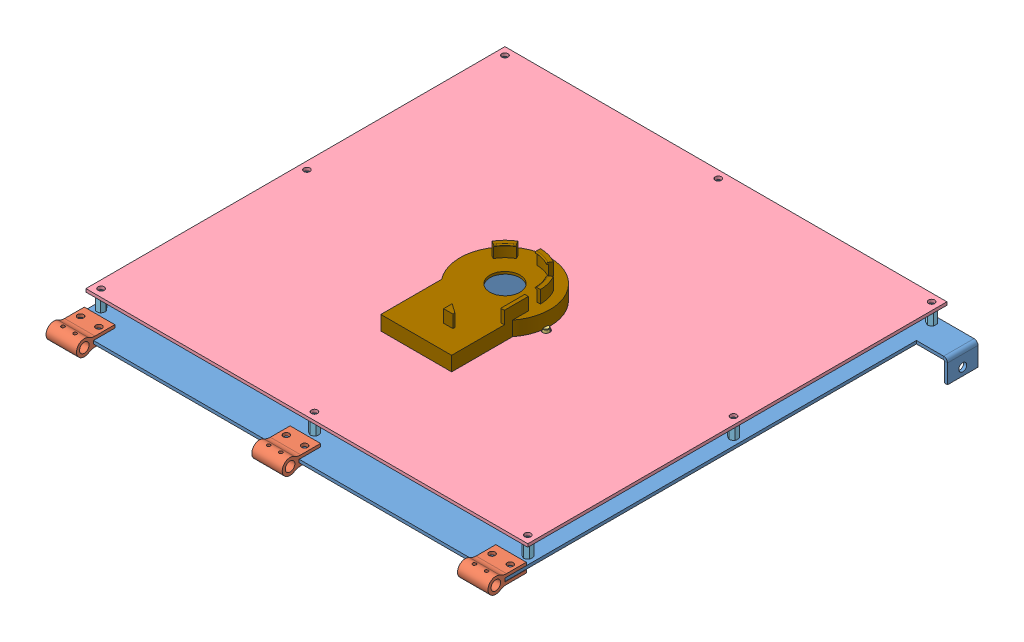
SolidWorks assembly WrenchPlateAssem, configuration Default. Lengths in mm.
Overall size (394.21 74.37 382.46).
21 component instances, 10 part files, 40 mates.
Components (placement in the parent):
- WrenchPlate-1: WrenchPlate [Default] at (-60.1457 196.6895 471.773) size (394.21 19.05 368.3)
- ShaftPanelHolder-1: ShaftPanelHolder [Default] at (282.7543 195.2925 479.393) x (0 -1 0) z (0 0 1) size (13.08 25.4 31.94)
- ShaftPanelHolder-2: ShaftPanelHolder [Default] at (111.3043 195.2925 479.393) x (0 -1 0) z (0 0 1) size (13.08 25.4 31.94)
- ShaftPanelHolder-3: ShaftPanelHolder [Default] at (-60.1457 195.2925 479.393) x (0 -1 0) z (0 0 1) size (13.08 25.4 31.94)
- StepperMotorNEMA17-1: StepperMotorNEMA17 [Default] at (161.6983 194.1495 291.0354) x (-1 0 0) z (0 1 0) size (41.78 41.78 53.06)
- BackPlate-1: BackPlate [Default] at (-60.1457 211.9295 471.773) x (0 -1 0) z (0 0 1) size (2.54 368.3 349.25)
- HexStandoff#6-1: HexStandoff#6 [91115A127] at (301.8043 203.0395 109.823) x (1 0 0) z (0 1 0) size (6.35 7.33 13.79)
- HexStandoff#6-2: HexStandoff#6 [91115A127] at (301.8043 203.0395 274.923) x (1 0 0) z (0 1 0) size (6.35 7.33 13.79)
- HexStandoff#6-3: HexStandoff#6 [91115A127] at (301.8043 203.0395 446.373) x (1 0 0) z (0 -1 0) size (6.35 7.33 13.79)
- HexStandoff#6-4: HexStandoff#6 [91115A127] at (124.0043 203.0395 446.373) x (1 0 0) z (0 -1 0) size (6.35 7.33 13.79)
- HexStandoff#6-5: HexStandoff#6 [91115A127] at (-53.7957 203.0395 446.373) x (0.932602 0 0.360906) z (0 -1 0) size (6.35 7.33 13.79)
- HexStandoff#6-6: HexStandoff#6 [91115A127] at (-53.7957 203.0395 274.923) x (1 0 0) z (0 -1 0) size (6.35 7.33 13.79)
- HexStandoff#6-7: HexStandoff#6 [91115A127] at (124.0043 203.0395 109.823) x (1 0 0) z (0 -1 0) size (6.35 7.33 13.79)
- HexStandoff#6-8: HexStandoff#6 [91115A127] at (-53.7957 203.0395 109.823) x (0.996245 0 -0.086583) z (0 1 0) size (6.35 7.33 13.79)
- StepperGearPitch241-1: StepperGearPitch241 [6832K62] at (161.6983 208.6275 291.0354) x (1 0 0) z (0 1 0) size (27.46 27.46 11.12)
- 8mmBallBearing-1: 8mmBallBearing [7804K147] at (124.0043 195.5495 287.623) x (-0.837169 0 -0.546944) z (0 1 0) size (18 18 5)
- 8mmBallBearing-2: 8mmBallBearing [7804K147] at (124.0043 210.5295 287.623) x (1 0 0) z (0 -1 0) size (18 18 5)
- StepperGearPitch24-2: StepperGearPitch24 [6832K65] at (124.0043 208.6275 287.623) x (-0.837169 0 -0.546944) z (0 1 0) size (52.9 52.9 11.14)
- WrenchHolderAssem-1: WrenchHolderAssem [Default] at (99.2433 158.6164 216.5098) size (75 47.9 111.45)
  - WrenchHolderV2-1: WrenchHolderV2 [Default] at (24.761 54.4131 71.1131) size (75 22.5 111.45)
  - Electromagnet-1: Electromagnet [Default] at (24.761 54.4131 71.1131) x (0.998284 0 -0.058561) z (0.058561 0 0.998284) size (70 35.4 70)
Mates (geometry in assembly coordinates):
- Coincident1: coincident anti-aligned: plane of WrenchPlate-1 through (-60.1457 194.1495 471.773) normal (0 0 1); plane of ShaftPanelHolder-3 through (-34.7457 193.8955 471.773) normal (0 0 -1)
- Coincident2: coincident anti-aligned: plane of WrenchPlate-1 through (-60.1457 196.6895 471.773) normal (0 1 0); plane of ShaftPanelHolder-3 through (-34.7457 196.6895 471.773) normal (0 -1 0)
- Coincident3: coincident aligned: plane of WrenchPlate-1 through (-60.1457 194.1495 471.773) normal (-1 0 0); plane of ShaftPanelHolder-3 through (-60.1457 181.1955 470.4395) normal (-1 0 0)
- Coincident4: coincident aligned: plane of WrenchPlate-1 through (308.1543 194.1495 471.773) normal (1 0 0); plane of ShaftPanelHolder-1 through (308.1543 181.1955 470.4395) normal (1 0 0)
- Coincident5: coincident anti-aligned: plane of WrenchPlate-1 through (-60.1457 194.1495 471.773) normal (0 0 1); plane of ShaftPanelHolder-1 through (308.1543 193.8955 471.773) normal (0 0 -1)
- Coincident6: coincident anti-aligned: plane of WrenchPlate-1 through (-60.1457 196.6895 471.773) normal (0 1 0); plane of ShaftPanelHolder-1 through (308.1543 196.6895 471.773) normal (0 -1 0)
- Coincident7: coincident anti-aligned: plane of WrenchPlate-1 through (-60.1457 194.1495 471.773) normal (0 0 1); plane of ShaftPanelHolder-2 through (136.7043 193.8955 471.773) normal (0 0 -1)
- Coincident8: coincident anti-aligned: plane of WrenchPlate-1 through (-60.1457 196.6895 471.773) normal (0 1 0); plane of ShaftPanelHolder-2 through (136.7043 196.6895 471.773) normal (0 -1 0)
- Distance1: distance = 171.45 mm aligned: plane of ShaftPanelHolder-2 through (136.7043 181.1955 470.4395) normal (1 0 0); plane of WrenchPlate-1 through (308.1543 194.1495 471.773) normal (1 0 0)
- Coincident13: coincident anti-aligned: plane of WrenchPlate-1 through (-60.1457 194.1495 471.773) normal (0 -1 0); plane of StepperMotorNEMA17-1 through (161.6983 194.1495 291.0354) normal (0 1 0)
- Distance5: distance = 164.211 mm: line of WrenchPlate-1 through (-60.1457 194.1495 471.773) axis (1 0 0); line of StepperMotorNEMA17-1 through (178.4259 161.1549 310.9109) axis (-1 0 0)
- Distance6: distance = 12.7 mm anti-aligned: plane of WrenchPlate-1 through (-60.1457 196.6895 471.773) normal (0 1 0); plane of BackPlate-1 through (-60.1457 209.3895 471.773) normal (0 -1 0)
- Coincident17: coincident aligned: plane of WrenchPlate-1 through (-60.1457 194.1495 471.773) normal (-1 0 0); plane of BackPlate-1 through (-60.1457 209.3895 471.773) normal (-1 0 0)
- Coincident18: coincident aligned: plane of WrenchPlate-1 through (-60.1457 194.1495 103.473) normal (0 0 -1); plane of BackPlate-1 through (-60.1457 209.3895 103.473) normal (0 0 -1)
- Coincident19: coincident anti-aligned: plane of WrenchPlate-1 through (-60.1457 196.6895 471.773) normal (0 1 0); plane of HexStandoff#6-1 through (301.8043 196.6895 106.1568) normal (0 -1 0)
- Coincident20: coincident anti-aligned: plane of WrenchPlate-1 through (-60.1457 196.6895 471.773) normal (0 1 0); plane of HexStandoff#6-2 through (301.8043 196.6895 271.2568) normal (0 -1 0)
- Concentric2: concentric aligned: circle of BackPlate-1; circle of HexStandoff#6-1
- Concentric3: concentric aligned: circle of BackPlate-1; circle of HexStandoff#6-2
- Coincident25: coincident anti-aligned: plane of WrenchPlate-1 through (-60.1457 196.6895 471.773) normal (0 1 0); plane of HexStandoff#6-3 through (301.8043 196.6895 450.0391) normal (0 -1 0)
- Concentric4: concentric anti-aligned: circle of BackPlate-1; circle of HexStandoff#6-3
- Coincident26: coincident anti-aligned: plane of WrenchPlate-1 through (-60.1457 196.6895 471.773) normal (0 1 0); plane of HexStandoff#6-4 through (124.0043 196.6895 450.0391) normal (0 -1 0)
- Concentric5: concentric anti-aligned: circle of BackPlate-1; circle of HexStandoff#6-4
- Coincident27: coincident anti-aligned: plane of WrenchPlate-1 through (-60.1457 196.6895 471.773) normal (0 1 0); plane of HexStandoff#6-5 through (-55.1189 196.6895 449.7921) normal (0 -1 0)
- Coincident29: coincident anti-aligned: plane of HexStandoff#6-6 through (-53.7957 196.6895 278.5891) normal (0 -1 0); plane of WrenchPlate-1 through (-60.1457 196.6895 471.773) normal (0 1 0)
- Concentric8: concentric anti-aligned: circle of BackPlate-1; circle of HexStandoff#6-6
- Concentric9: concentric aligned: circle of BackPlate-1; cone of HexStandoff#6-7 through (124.0043 209.3895 109.823) axis (0 -1 0)
- Coincident33: coincident anti-aligned: plane of WrenchPlate-1 through (-60.1457 196.6895 471.773) normal (0 1 0); plane of HexStandoff#6-7 through (124.0043 196.6895 113.4891) normal (0 -1 0)
- Concentric10: concentric anti-aligned: circle of BackPlate-1; circle of HexStandoff#6-5
- Concentric11: concentric anti-aligned: circle of BackPlate-1; circle of HexStandoff#6-8
- Coincident34: coincident anti-aligned: plane of WrenchPlate-1 through (-60.1457 196.6895 471.773) normal (0 1 0); plane of HexStandoff#6-8 through (-54.1132 196.6895 106.1706) normal (0 -1 0)
- Distance9: distance = 0.762 mm anti-aligned: plane of StepperGearPitch241-1 through (161.6983 208.6275 291.0354) normal (0 1 0); plane of BackPlate-1 through (-60.1457 209.3895 471.773) normal (0 -1 0)
- Concentric14: concentric anti-aligned: cylinder of StepperMotorNEMA17-1 through (161.6983 186.1765 291.0354) axis (0 -1 0) radius 2.4956; cylinder of StepperGearPitch241-1 through (161.6983 203.865 291.0354) axis (0 1 0) radius 6.35
- Coincident37: coincident anti-aligned: circle of BackPlate-1; circle of 8mmBallBearing-2
- Concentric15: concentric aligned: circle of WrenchPlate-1; circle of 8mmBallBearing-1
- Coincident38: coincident aligned: plane of WrenchPlate-1 through (-60.1457 194.1495 471.773) normal (0 -1 0); circle of 8mmBallBearing-1
- Concentric16: concentric aligned: circle of 8mmBallBearing-2; circle of StepperGearPitch24-2
- Distance10: distance = 0.762 mm anti-aligned: plane of StepperGearPitch24-2 through (124.0043 208.6275 287.623) normal (0 1 0); plane of BackPlate-1 through (-60.1457 209.3895 471.773) normal (0 -1 0)
- Distance11: distance = 130.81 mm: line of StepperMotorNEMA17-1 through (181.5738 161.1549 274.3078) axis (0 0 1); line of WrenchPlate-1 through (308.1543 194.1495 471.773) axis (0 0 -1)
- Concentric17: concentric aligned: cylinder of 8mmBallBearing-1 through (124.0043 198.0495 287.623) axis (0 1 0) radius 4; cylinder of WrenchHolderAssem-1/Electromagnet-1 through (124.0043 187.6295 287.623) axis (0 1 0) radius 4
- Coincident39: coincident anti-aligned: plane of 8mmBallBearing-2 through (124.0043 213.0295 295.373) normal (0 1 0); plane of WrenchHolderAssem-1/Electromagnet-1 through (124.0043 213.0295 287.623) normal (0 -1 0)
